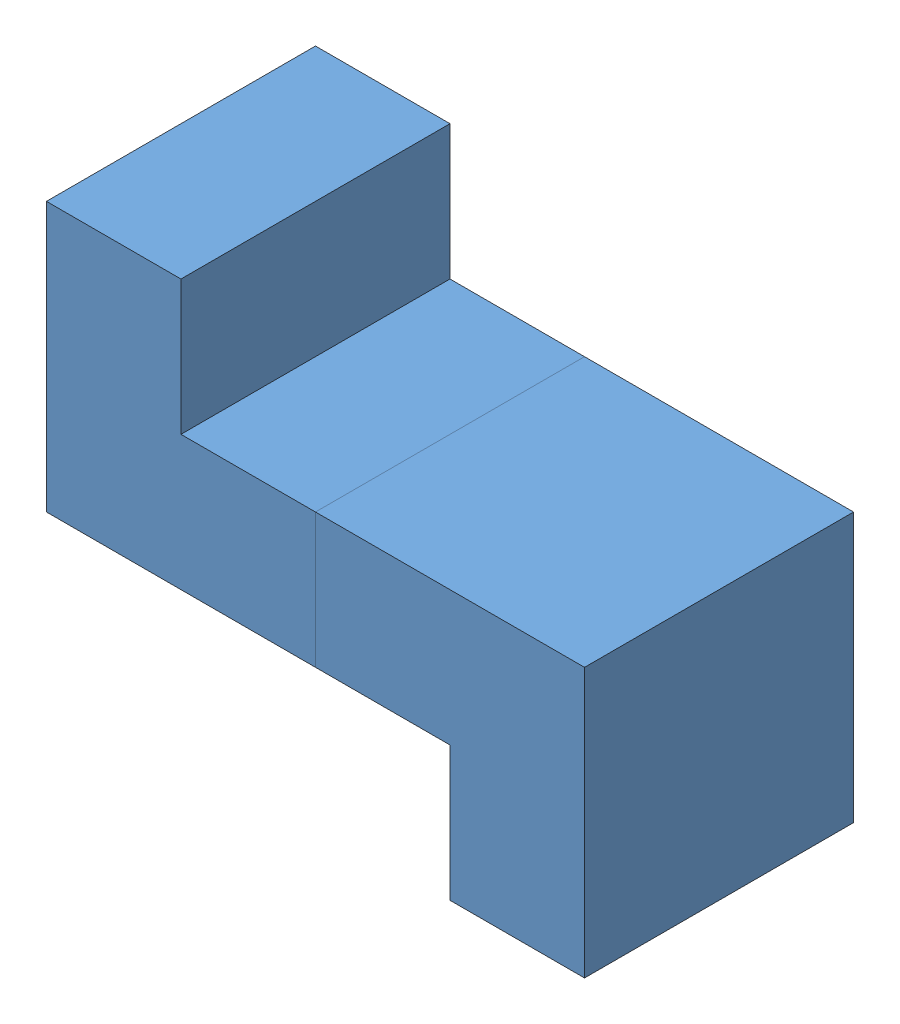
SolidWorks assembly Lecture5_assembledblock_21010264, configuration Default. Lengths in mm.
Overall size (160 120 80).
2 component instances, 1 part files, 3 mates.
Components (placement in the parent):
- Lecture5_partblock_21010264-3: Lecture5_partblock_21010264 [Default] at origin size (80 80 80)
- Lecture5_partblock_21010264-4: Lecture5_partblock_21010264 [Default] at (160 40 0) x (-1 0 0) z (0 0 1) size (80 80 80)
Mates (geometry in assembly coordinates):
- Coincident2: coincident: plane of Lecture5_partblock_21010264-3 through (0 0 0) normal (0 0 1); plane of Lecture5_partblock_21010264-4 through (160 80 0) normal (0 0 1)
- Coincident4: coincident: plane of Lecture5_partblock_21010264-3 through (80 0 -80) normal (1 0 0); plane of Lecture5_partblock_21010264-4 through (80 80 -80) normal (-1 0 0)
- Coincident5: coincident aligned: plane of Lecture5_partblock_21010264-3 through (80 40 -80) normal (0 1 0); plane of Lecture5_partblock_21010264-4 through (160 40 -80) normal (0 1 0)
